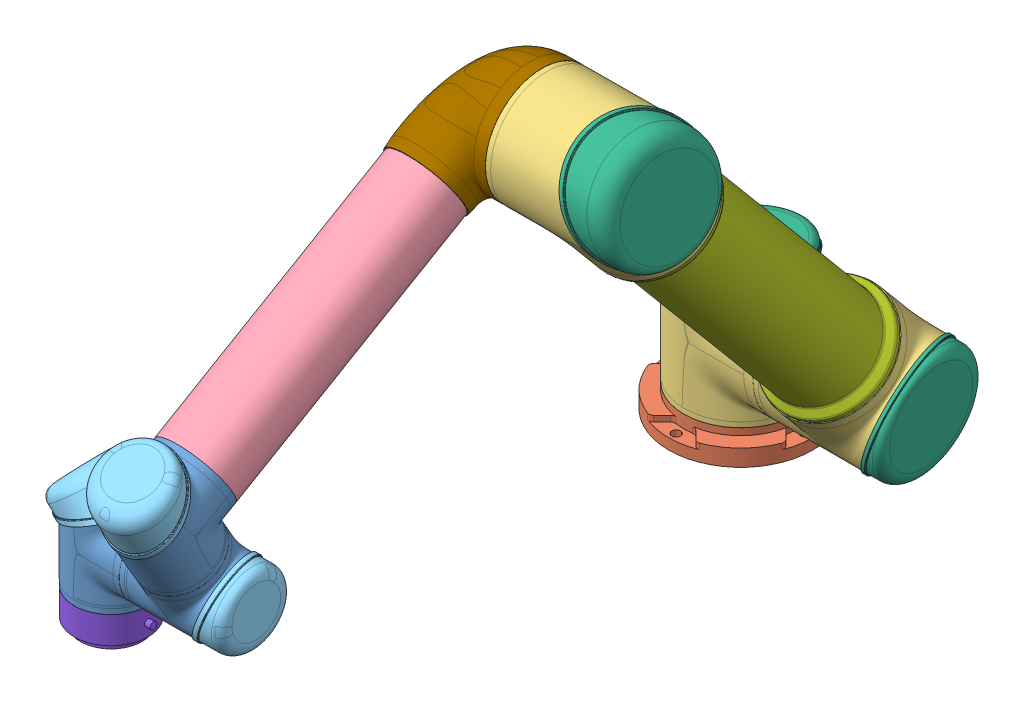
SolidWorks assembly UR5, configuration Default. Lengths in mm.
Overall size (344.78 499.9 760.49).
17 component instances, 9 part files, 45 mates.
Components (placement in the parent):
- Size 1_House_r13_Simple-1: Size 1_House_r13_Simple [Default] at (17.3569 137.7558 566.8462) x (-0.000585 0.866025 0.500001) z (-0.003317 0.499996 -0.866021) size (83 87.5 79.44)
- Size 1_House_r13_Simple-2: Size 1_House_r13_Simple [Default] at (-75.6425 137.5544 567.0862) x (0.999994 0.002165 -0.002581) z (0.002581 0.000003 0.999997) size (83 87.5 79.44)
- Size 3_Round base_r02_Simple-1: Size 3_Round base_r02_Simple [Default] at (0 3 0) x (0 -1 0) z (0 0 -1) size (24 154.92 154.92)
- Size 3_House_r11_Simple-1: Size 3_House_r11_Simple [Default] at (135.7 414.7689 273.1847) x (-0.999994 -0.002165 0.002581) z (-0.003369 0.642784 -0.76604) size (129.79 128.5 124.27)
- Size 1 r¬r_r01_Simple-1: Size 1 r¬r_r01_Simple [Default] at (16.6562 315.7154 444.6107) x (-0.999994 -0.002165 0.002581) z (0.003317 -0.499996 0.866021) size (75 75 272.93)
- Size 1_Joint lid_r07_Simple-1: Size 1_Joint lid_r07_Simple [Default] at (17.3025 218.2961 613.3463) x (-0.003317 0.499996 -0.866021) z (0.999994 0.002165 -0.002581) size (77.51 51.3 77.52)
- Size 3_Joint lid_r06_Simple-1: Size 3_Joint lid_r06_Simple [Default] at (135.7003 89.2 0) x (-1 0 0) z (0 -0.642788 0.766044) size (62.7 119 119.01)
- Size 1_House_r13_Simple-3: Size 1_House_r13_Simple [Default] at (17.3025 218.2961 613.3463) x (-0.003317 0.499996 -0.866021) z (0.999994 0.002165 -0.002581) size (83 87.5 79.44)
- Size 3_House_r11_Simple-2: Size 3_House_r11_Simple [Default] at (135.7 89.2 0) x (-1 0 0) z (0 -0.642788 0.766044) size (129.79 128.5 124.27)
- Size 3_Over arm_r01_Simpel-1: Size 3_Over arm_r01_Simpel [Default] at (135.7 251.9844 136.5924) x (0 -0.766044 -0.642788) z (-0.756553 0.42034 -0.500941) size (284 114.3 114.3)
- Size 3_House_r11_Simple-3: Size 3_House_r11_Simple [Default] at (0 89.2 0) x (0 -1 0) z (0 0 -1) size (129.79 128.5 124.27)
- Size 1_Joint lid_r07_Simple-2: Size 1_Joint lid_r07_Simple [Default] at (-59.9925 144.481 567.0458) x (-0.674003 -0.738727 0.001741) z (-0.002581 -0.000003 -0.999997) size (77.51 51.3 77.52)
- Size 3_Joint lid_r06_Simple-2: Size 3_Joint lid_r06_Simple [Default] at (135.0062 415.9165 274.1507) x (-0.999994 -0.002165 0.002581) z (-0.003369 0.642784 -0.76604) size (62.7 119 119.01)
- Size 1_Tool flange_r03_Simple-1: Size 1_Tool flange_r03_Simple [Default] at (-75.5397 90.0545 567.0861) x (0.002165 -0.999998 -0.000003) z (0.002581 0.000003 0.999997) size (34.5 80.5 75)
- Size 1_Joint lid_r07_Simple-3: Size 1_Joint lid_r07_Simple [Default] at (17.3569 137.7558 566.8462) x (-0.000585 0.866025 0.500001) z (-0.003317 0.499996 -0.866021) size (77.51 51.3 77.52)
- Size 3 to Size 1_Angle_r02_Simple-1: Size 3 to Size 1_Angle_r02_Simple [Default] at (16.0007 414.5097 273.4936) x (-0.003317 0.499996 -0.866021) z (-0.000585 0.866025 0.500001) size (132.01 97.09 116.02)
- Size 3_Joint lid_r06_Simple-3: Size 3_Joint lid_r06_Simple [Default] at (-1.5 88.5062 0) x (0 -1 0) z (0 0 -1) size (62.7 119 119.01)
Mates (geometry in assembly coordinates):
- Theta1: planar angle = 0 rad anti-aligned: plane of Size 3_House_r11_Simple-3 through (0 89.2 0) normal (0 0 -1); plane of assembly through (0 0 0) normal (0 0 1)
- Theta2: planar angle = 2.443461 rad aligned: plane of Size 3_House_r11_Simple-2 through (135.7 89.2 0) normal (0 -0.642788 0.766044); plane of Size 3_House_r11_Simple-3 through (0 89.2 0) normal (0 0 -1)
- Theta3: planar angle = 1.396263 rad aligned: plane of Size 3_House_r11_Simple-1 through (135.7 414.7689 273.1847) normal (-0.003369 0.642784 -0.76604); plane of Size 3 to Size 1_Angle_r02_Simple-1 through (16.0007 414.5097 273.4936) normal (-0.000585 0.866025 0.500001)
- Theta4: planar angle = 1.570796 rad anti-aligned: plane of Size 1_House_r13_Simple-1 through (17.3569 137.7558 566.8462) normal (-0.003317 0.499996 -0.866021); plane of Size 1_House_r13_Simple-3 through (17.3025 218.2961 613.3463) normal (0.999994 0.002165 -0.002581)
- Theta5: planar angle = 0.523599 rad anti-aligned: plane of Size 1_House_r13_Simple-1 through (17.3569 137.7558 566.8462) normal (-0.003317 0.499996 -0.866021); plane of Size 1_House_r13_Simple-2 through (-75.6425 137.5544 567.0862) normal (0.002581 0.000003 0.999997)
- Theta6: planar angle = 0 rad aligned: plane of Size 1_House_r13_Simple-2 through (-75.6425 137.5544 567.0862) normal (0.002581 0.000003 0.999997); plane of Size 1_Tool flange_r03_Simple-1 through (-75.5397 90.0545 567.0861) normal (0.002581 0.000003 0.999997)
- Joint1: concentric aligned: cylinder of Size 3_Round base_r02_Simple-1 through (0 0 0) axis (0 1 0) radius 58; circle of Size 3_House_r11_Simple-3
- Joint 2: concentric anti-aligned: cylinder of Size 3_House_r11_Simple-2 through (70.5 89.2 0) axis (1 0 0) radius 57.9; cylinder of Size 3_House_r11_Simple-3 through (234.5488 89.2 0) axis (-1 0 0) radius 58
- Joint 3: concentric anti-aligned: cylinder of Size 3_House_r11_Simple-1 through (-54.9909 414.356 273.6768) axis (0.999994 0.002165 -0.002581) radius 58; cylinder of Size 3 to Size 1_Angle_r02_Simple-1 through (61.5004 414.6082 273.3762) axis (-0.999994 -0.002165 0.002581) radius 58
- Joint 4: concentric aligned: circle of Size 1_House_r13_Simple-1; cylinder of Size 1_House_r13_Simple-3 through (17.3303 177.1599 589.5963) axis (-0.000585 0.866025 0.500001) radius 37.4
- Joint 5: concentric aligned: cylinder of Size 1_House_r13_Simple-1 through (-30.1428 137.653 566.9688) axis (0.999994 0.002165 -0.002581) radius 37.4; circle of Size 1_House_r13_Simple-2
- Joint 6: concentric aligned: cylinder of Size 1_House_r13_Simple-2 through (-75.5397 90.0545 567.0861) axis (-0.002165 0.999998 0.000003) radius 37.4; cylinder of Size 1_Tool flange_r03_Simple-1 through (-75.5397 90.0545 567.0861) axis (-0.002165 0.999998 0.000003) radius 37.5
- Coincident: coincident anti-aligned: plane of Size 1 r¬r_r01_Simple-1; plane of Size 1_House_r13_Simple-3 through (17.3025 218.2961 613.3463) normal (0.999994 0.002165 -0.002581)
- Coincident4: coincident anti-aligned: plane of Size 3_Round base_r02_Simple-1 through (-56.1 24 0) normal (0 1 0); plane of Size 3_House_r11_Simple-3 through (0 24 0) normal (0 -1 0)
- Coincident6: coincident anti-aligned: plane of Size 3_House_r11_Simple-3 through (-12.8099 116.8832 0) normal (-0.41995 0.907547 0); plane of Size 3_Joint lid_r06_Simple-3 through (-66.9469 91.8323 -279.4671) normal (0.41995 -0.907547 0)
- Tangent3: tangent: curve of ?; cylinder of Size 3_Joint lid_r06_Simple-3 through (-1.5 93.2006 0) axis (0 1 0) radius 59.5
- Coincident7: coincident anti-aligned: plane of Size 3_House_r11_Simple-2 through (70.5 89.2 0) normal (-1 0 0); plane of Size 3_House_r11_Simple-3 through (70.5 89.2 0) normal (1 0 0)
- Coincident8: coincident anti-aligned: plane of Size 3_Joint lid_r06_Simple-1 through (139.0264 -140.5733 172.0158) normal (-0.907547 0.3217 0.269939); plane of Size 3_House_r11_Simple-2 through (163.3832 79.3871 -8.234) normal (0.907547 -0.3217 -0.269939)
- Concentric5: concentric aligned: cylinder of Size 3_Joint lid_r06_Simple-1 through (140.3947 89.2 0) axis (1 0 0) radius 59.5; cylinder of Size 3_House_r11_Simple-2 through (-54.9919 89.2 0) axis (1 0 0) radius 58
- Coincident9: coincident anti-aligned: plane of Size 3_House_r11_Simple-2 through (135.7 143.2061 45.3165) normal (0 0.766044 0.642788); plane of Size 3_Over arm_r01_Simpel-1 through (172.9742 170.9254 12.282) normal (0 -0.766044 -0.642788)
- Concentric6: concentric aligned: cylinder of Size 3_House_r11_Simple-2 through (135.7 268.8748 150.765) axis (0 -0.766044 -0.642788) radius 58; cylinder of Size 3_Over arm_r01_Simpel-1 through (135.7 251.9844 136.5924) axis (0 -0.766044 -0.642788) radius 57.15
- Coincident10: coincident anti-aligned: plane of Size 3_House_r11_Simple-1 through (135.7 360.7628 227.8682) normal (0 -0.766044 -0.642788); plane of Size 3_Over arm_r01_Simpel-1 through (172.9742 388.482 194.8337) normal (0 0.766044 0.642788)
- Concentric7: concentric anti-aligned: cylinder of Size 3_House_r11_Simple-1 through (135.7 235.0941 122.4197) axis (0 0.766044 0.642788) radius 58; cylinder of Size 3_Over arm_r01_Simpel-1 through (135.7 251.9844 136.5924) axis (0 -0.766044 -0.642788) radius 57.15
- Coincident11: coincident anti-aligned: plane of Size 3_House_r11_Simple-1 through (163.383 424.6417 281.3473) normal (0.907542 0.323665 0.267597); plane of Size 3_Joint lid_r06_Simple-2 through (137.3909 645.6959 102.1276) normal (-0.907542 -0.323665 -0.267597)
- Coincident13: coincident anti-aligned: plane of Size 3_House_r11_Simple-1 through (70.5004 414.6277 273.353) normal (-0.999994 -0.002165 0.002581); plane of Size 3 to Size 1_Angle_r02_Simple-1 through (70.5004 414.6277 273.353) normal (0.999994 0.002165 -0.002581)
- Coincident14: coincident anti-aligned: plane of Size 1 r¬r_r01_Simple-1 through (16.2681 345.034 318.8292) normal (-0.003317 0.499996 -0.866021); plane of Size 3 to Size 1_Angle_r02_Simple-1 through (16.2462 377.51 337.5792) normal (0.003317 -0.499996 0.866021)
- Concentric9: concentric anti-aligned: cylinder of Size 1 r¬r_r01_Simple-1 through (17.1491 241.4209 573.2928) axis (-0.003317 0.499996 -0.866021) radius 37.5; cone of Size 3 to Size 1_Angle_r02_Simple-1 through (16.213 382.5099 328.919) axis (0.003317 -0.499996 0.866021)
- Coincident16: coincident anti-aligned: plane of Size 1 r¬r_r01_Simple-1 through (17.1516 241.0459 573.9423) normal (0.003317 -0.499996 0.866021); plane of Size 1_House_r13_Simple-3 through (17.1516 241.0459 573.9423) normal (-0.003317 0.499996 -0.866021)
- Concentric20: concentric aligned: cylinder of Size 1 r¬r_r01_Simple-1 through (17.1491 241.4209 573.2928) axis (-0.003317 0.499996 -0.866021) radius 37.5; circle of Size 1_House_r13_Simple-3
- Concentric10: concentric aligned: cylinder of Size 1_Joint lid_r07_Simple-1 through (17.2994 222.987 616.0546) axis (-0.000585 0.866025 0.500001) radius 38.75; cylinder of Size 1_House_r13_Simple-3 through (17.3336 172.3682 586.8297) axis (-0.000585 0.866025 0.500001) radius 37.5
- Coincident17: coincident anti-aligned: plane of Size 1_Joint lid_r07_Simple-1 through (171.8263 275.5473 597.2664) normal (-0.000801 -0.591318 -0.806438); plane of Size 1_House_r13_Simple-3 through (17.3194 230.7196 630.2895) normal (0.000801 0.591318 0.806438)
- Coincident18: coincident anti-aligned: plane of Size 1_House_r13_Simple-1 through (17.3303 177.1599 589.5963) normal (-0.000585 0.866025 0.500001); plane of Size 1_House_r13_Simple-3 through (17.3303 177.1599 589.5963) normal (0.000585 -0.866025 -0.500001)
- Coincident19: coincident anti-aligned: plane of Size 1_House_r13_Simple-1 through (36.5925 130.4696 562.5658) normal (0.915545 -0.3468 -0.203732); plane of Size 1_Joint lid_r07_Simple-3 through (58.2695 251.5954 453.7951) normal (-0.915545 0.3468 0.203732)
- Concentric12: concentric aligned: cylinder of Size 1_House_r13_Simple-1 through (-35.6758 137.641 566.9831) axis (0.999994 0.002165 -0.002581) radius 37.5; cylinder of Size 1_Joint lid_r07_Simple-3 through (22.7734 137.7675 566.8322) axis (0.999994 0.002165 -0.002581) radius 38.75
- Coincident20: coincident anti-aligned: plane of Size 1_House_r13_Simple-1 through (-30.1428 137.653 566.9688) normal (-0.999994 -0.002165 0.002581); plane of Size 1_House_r13_Simple-2 through (-30.1428 137.653 566.9688) normal (0.999994 0.002165 -0.002581)
- Coincident22: coincident anti-aligned: plane of Size 1_House_r13_Simple-2 through (-75.5397 90.0545 567.0861) normal (0.002165 -0.999998 -0.000003); plane of Size 1_Tool flange_r03_Simple-1 through (-38.0399 90.1357 566.9893) normal (-0.002165 0.999998 0.000003)
- Coincident26: coordinate: point of Size 3_Round base_r02_Simple-1; point of assembly
- Coincident28: coincident anti-aligned: plane of Size 1_House_r13_Simple-2 through (-75.6425 137.5544 567.0862) normal (0.002581 0.000003 0.999997); plane of Size 1_Joint lid_r07_Simple-2 through (-59.9925 144.481 567.0458) normal (-0.002581 -0.000003 -0.999997)
- Coincident29: coincident anti-aligned: plane of Size 1_House_r13_Simple-2 through (-84.1456 156.7667 567.1081) normal (-0.404718 0.914441 0.001042); plane of Size 1_Joint lid_r07_Simple-2 through (-119.3462 141.3636 412.5101) normal (0.404718 -0.914441 -0.001042)
- Tangent14: tangent: curve of Size 1_House_r13_Simple-2; curve of Size 1_Joint lid_r07_Simple-2
- Coincident30: coincident aligned: plane of Size 3_House_r11_Simple-1 through (135.7 414.7689 273.1847) normal (-0.003369 0.642784 -0.76604); plane of Size 3_Joint lid_r06_Simple-2 through (135.0062 415.9165 274.1507) normal (-0.003369 0.642784 -0.76604)
- Tangent17: tangent: curve of Size 3_House_r11_Simple-1; curve of Size 3_Joint lid_r06_Simple-2
- Coincident32: coincident aligned: plane of Size 3_House_r11_Simple-3 through (0 89.2 0) normal (0 0 -1); plane of Size 3_Joint lid_r06_Simple-3 through (-1.5 88.5062 0) normal (0 0 -1)
- Coincident34: coincident aligned: plane of Size 1 r¬r_r01_Simple-1; plane of Size 3 to Size 1_Angle_r02_Simple-1
- Coincident35: coincident anti-aligned: plane of Size 1_House_r13_Simple-2 through (-75.6425 137.5544 567.0862) normal (0.002581 0.000003 0.999997); plane of Size 1_Joint lid_r07_Simple-2 through (-59.9925 144.481 567.0458) normal (-0.002581 -0.000003 -0.999997)
